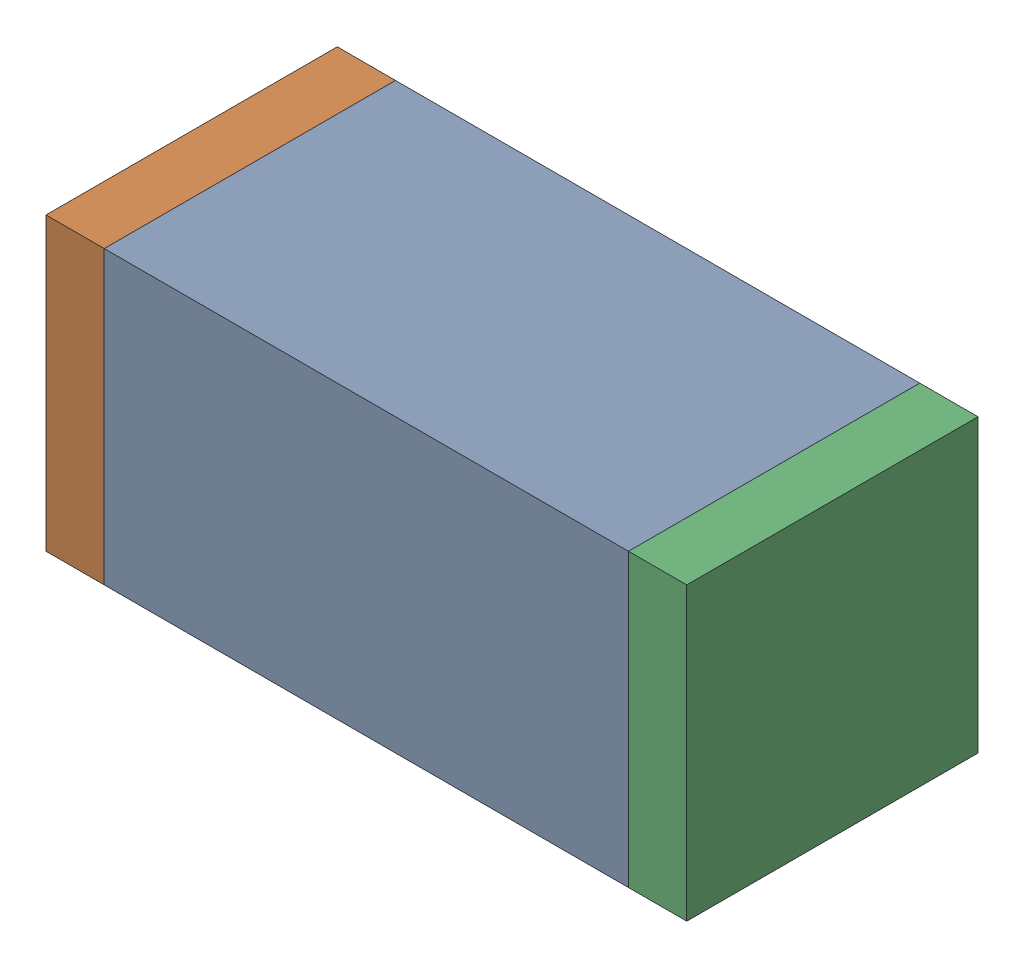
SolidWorks assembly C47, configuration Default. Lengths in mm.
Overall size (1.1 0.5 0.5).
6 component instances, 2 part files, 0 mates.
Components (placement in the parent):
- 836749680-1: 836749680 [Default] at (106.8 39.55 0) size (0.9 0.5 0.5)
  - Extruded_4-1: Extruded_4 [Default] at origin size (0.9 0.5 0.5)
- 810156080-1: 810156080 [Default] at (106.3 39.55 0) size (0.1 0.5 0.5)
  - Extruded_5-1: Extruded_5 [Default] at origin size (0.1 0.5 0.5)
- 810156080-2: 810156080 [Default] at (107.3 39.55 0) size (0.1 0.5 0.5)
  - Extruded_5-1: Extruded_5 [Default] at origin size (0.1 0.5 0.5)
